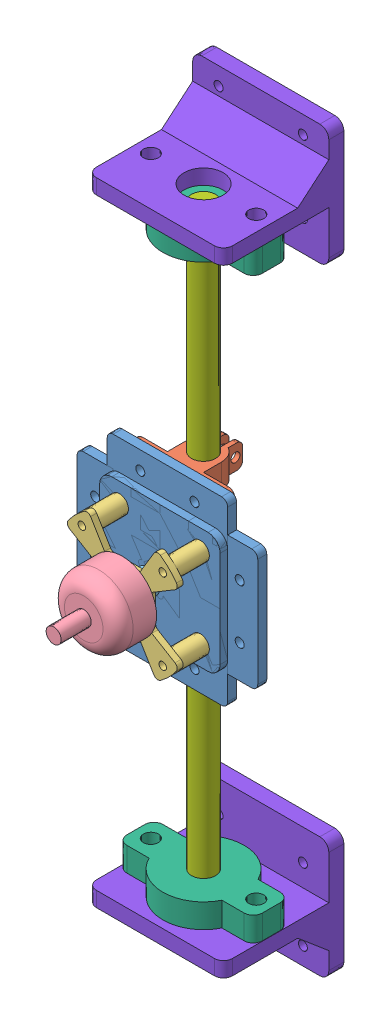
SolidWorks assembly 单轴测试架, configuration 默认. Lengths in mm.
Overall size (82.25 245 73.8).
13 component instances, 8 part files, 24 mates.
Components (placement in the parent):
- 底座-1: 底座 [默认] at (871.0089 112.5711 -134.5979) size (40 60 5.5)
- 底座_测试架_连接件-1: 底座_测试架_连接件 [默认] at (829.6728 169.8652 -140.5979) x (1 0 0) z (0 0 -1) size (32.68 8 19)
- 底座_测试架_连接件-2: 底座_测试架_连接件 [默认] at (822.2194 69.1481 -140.5979) x (-1 0 0) z (0 0 -1) size (32.68 8 19)
- 电机_固定座_装配体-1: 电机_固定座_装配体 [默认] at (832.9186 126.7759 -169.8479) x (0.707107 0.707107 0) z (0 0 1) size (70.71 70.71 40.8)
  - B2212电机固定-1: B2212电机固定 [默认] at (-10.0704 -0.2098 48.25) size (44 44 12.5)
  - 1804无刷电机-1: 1804无刷电机 [默认] at (-10.0704 -0.2098 50.25) size (22.8 22.8 24.3)
  - 磁铁安装件-1: 磁铁安装件 [默认] at (-10.0704 -0.2098 45.75) x (-0.755076 -0.655637 0) z (0 0 -1) size (8 8 8)
  - 底座-1: 底座 [默认] at (26.698 26.7503 35.25) x (0.707107 0.707107 0) z (0 0 1) size (40 60 5.5)
- 卧式轴承8mm-1: 卧式轴承8mm [默认] at (825.9461 27.5067 -146.5979) x (1 0 0) z (0 -1 0) size (45 27 8)
- 8mmX200mm轴-1: 8mmX200mm轴 [默认] at (825.9461 19.5067 -146.5979) size (8 200 8)
- 卧式轴承8mm-2: 卧式轴承8mm [默认] at (825.9461 211.5067 -146.5979) x (1 0 0) z (0 1 0) size (45 27 8)
- 卧式轴承固定件-1: 卧式轴承固定件 [默认] at (76.629 14.5067 77.5005) size (45.23 40 40)
- 卧式轴承固定件-2: 卧式轴承固定件 [默认] at (1575.2631 224.5067 77.5005) x (-1 0 0) z (0 0 1) size (45.23 40 40)
Mates (geometry in assembly coordinates):
- 重合1: coincident: plane of assembly; plane of assembly; plane of 底座-1 through (871.0089 112.5711 -137.5979) normal (0 0 -1); plane of 底座_测试架_连接件-1 through (829.6728 169.8652 -137.5979) normal (0 0 1)
- 平行1: parallel: plane of assembly; plane of assembly; plane of 底座-1 through (805.9461 149.5067 -137.5979) normal (0 1 0); plane of 底座_测试架_连接件-1 through (809.6074 147.5067 -137.5979) normal (0 1 0)
- 同心2: concentric: circle of assembly; circle of assembly; circle of 底座-1; circle of 底座_测试架_连接件-1
- 重合5: coincident: plane of assembly; plane of assembly; plane of 底座-1 through (871.0089 112.5711 -137.5979) normal (0 0 -1); plane of 底座_测试架_连接件-2 through (822.2194 69.1481 -137.5979) normal (0 0 1)
- 同心3: concentric: circle of assembly; circle of assembly; circle of 底座-1; circle of 底座_测试架_连接件-2
- 同心4: concentric: circle of assembly; circle of assembly; circle of 底座-1; circle of 底座_测试架_连接件-2
- 同心5: concentric: circle of assembly; circle of assembly; circle of 底座-1; circle of 电机_固定座_装配体-1/B2212电机固定-1
- 同心6: concentric: circle of assembly; circle of assembly; circle of 底座-1; circle of 电机_固定座_装配体-1/B2212电机固定-1
- 重合6: coincident: plane of assembly; plane of assembly; plane of 底座-1 through (871.0089 112.5711 -132.0979) normal (0 0 1); plane of 电机_固定座_装配体-1/B2212电机固定-1 through (812.5111 132.9417 -132.0979) normal (0 0 -1)
- 同心7: concentric: circle of assembly; circle of assembly; circle of 底座_测试架_连接件-2; circle of 卧式轴承8mm-1
- 对称2: symmetric: plane of assembly; plane of assembly; plane of 底座-1 through (805.9461 89.5067 -137.5979) normal (0 -1 0); plane of 底座-1 through (805.9461 149.5067 -137.5979) normal (0 1 0); plane of assembly
- 同心9: concentric: circle of assembly; circle of assembly; circle of 底座_测试架_连接件-1; circle of 8mmX200mm轴-1
- 平行2: parallel: plane of assembly; plane of assembly; plane of 底座-1 through (871.0089 112.5711 -137.5979) normal (0 0 -1); plane of 卧式轴承8mm-1 through (848.4461 74.0792 -140.5979) normal (0 0 1)
- 同心10: concentric: circle of assembly; circle of assembly; circle of 8mmX200mm轴-1; circle of 卧式轴承8mm-2
- 同心11: concentric: circle of assembly; circle of assembly; circle of 卧式轴承8mm-1; circle of 卧式轴承8mm-2
- 重合13: coincident: plane of assembly; plane of assembly; plane of 8mmX200mm轴-1 through (825.9461 219.5067 -146.5979) normal (0 1 0); plane of 卧式轴承8mm-2 through (825.9461 219.5067 -146.5979) normal (0 1 0)
- 重合14: coincident: plane of assembly; circle of assembly; plane of 卧式轴承8mm-1 through (825.9461 19.5067 -146.5979) normal (0 -1 0); circle of 8mmX200mm轴-1
- 重合15: coincident: plane of assembly; plane of assembly; plane of 卧式轴承8mm-1 through (825.9461 19.5067 -146.5979) normal (0 -1 0); plane of 卧式轴承固定件-1 through (76.629 19.5067 77.5005) normal (0 1 0)
- 平行3: parallel: plane of assembly; plane of assembly; plane of 卧式轴承8mm-1 through (803.4461 74.0792 -152.5979) normal (-1 0 0); plane of 卧式轴承固定件-1 through (803.3293 19.5067 -130.5955) normal (-1 0 0)
- 同心13: concentric: circle of assembly; circle of assembly; circle of 卧式轴承8mm-1; circle of 卧式轴承固定件-1
- 同心14: concentric: circle of assembly; circle of assembly; circle of 卧式轴承8mm-1; circle of 卧式轴承固定件-1
- 同心15: concentric: circle of assembly; circle of assembly; circle of 卧式轴承固定件-2; circle of 卧式轴承8mm-2
- 同心17: concentric: circle of assembly; circle of assembly; circle of 卧式轴承8mm-2; circle of 卧式轴承固定件-2
- 重合23: coincident: plane of assembly; plane of assembly; plane of 卧式轴承8mm-2 through (825.9461 219.5067 -146.5979) normal (0 1 0); plane of 卧式轴承固定件-2 through (1575.2631 219.5067 77.5005) normal (0 -1 0)
